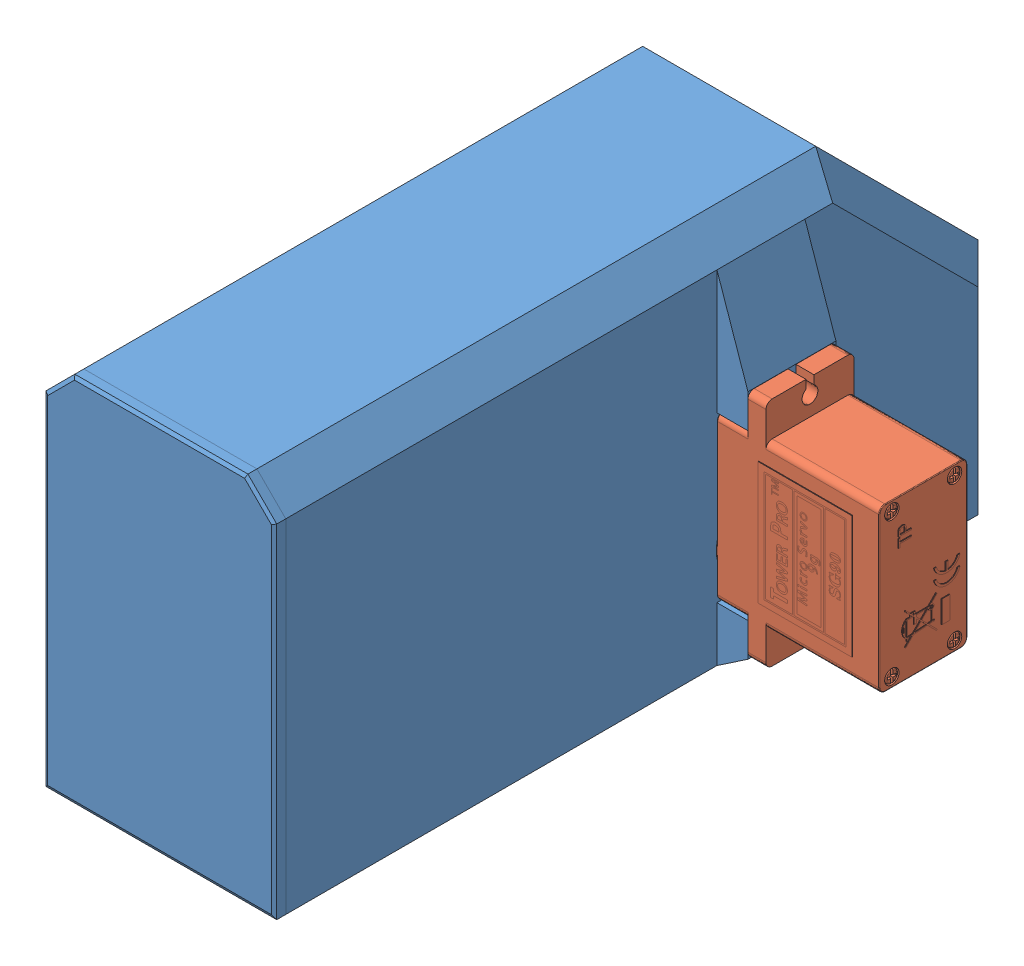
SolidWorks assembly Сборка1, configuration По умолчанию. Lengths in mm.
Overall size (58.9 54.12 101.5).
4 component instances, 4 part files, 9 mates.
Components (placement in the parent):
- кормушка 2-1: кормушка 2 [По умолчанию] at origin size (40.6 51.52 101.5)
- SG90 - Micro Servo 9g - Tower Pro-1: SG90 - Micro Servo 9g - Tower Pro [По умолчанию] at (44.7678 -13.4833 6.3168) x (0 1 0) z (0 0 1) size (32.1 29.95 12.4)
- SG90 - Micro Servo 9g - Tower Pro.3-1: SG90 - Micro Servo 9g - Tower Pro.3 [Peça] at (6.85 -11.96 34.1) x (0 -0.98697 -0.160905) z (0 0.160905 -0.98697) size (32.1 3.8 6.9)
- вал-1: вал [По умолчанию] at (-16 -11.96 34.1) x (0 -1 0) z (1 0 0) size (16.4 16.4 28.15)
Mates (geometry in assembly coordinates):
- Параллельность1: parallel aligned: plane of кормушка 2-1 through (0 0 100) normal (0 0 1); plane of SG90 - Micro Servo 9g - Tower Pro-1 through (22.8 -17.21 40.2) normal (0 0 1)
- Совпадение3: coincident anti-aligned: plane of кормушка 2-1 through (16 25.76 100) normal (1 0 0); plane of SG90 - Micro Servo 9g - Tower Pro-1 through (16 -17.21 39.35) normal (-1 0 0)
- Расстояние1: distance = 2.9 mm aligned: plane of SG90 - Micro Servo 9g - Tower Pro-1 through (20.3 -22.86 39.35) normal (0 -1 0); plane of кормушка 2-1 through (-16 -25.76 100) normal (0 -1 0)
- Совпадение5: coincident aligned: plane of кормушка 2-1 through (20.3 -25.76 28) normal (0 0 -1); plane of SG90 - Micro Servo 9g - Tower Pro-1 through (22.8 -17.21 28) normal (0 0 -1)
- Концентричный1: concentric aligned: circle of SG90 - Micro Servo 9g - Tower Pro-1; circle of SG90 - Micro Servo 9g - Tower Pro.3-1
- Совпадение6: coincident anti-aligned: plane of SG90 - Micro Servo 9g - Tower Pro-1 through (8.65 -11.96 34.1) normal (-1 0 0); plane of SG90 - Micro Servo 9g - Tower Pro.3-1 through (8.65 -11.96 34.1) normal (1 0 0)
- Концентричный2: concentric anti-aligned: circle of SG90 - Micro Servo 9g - Tower Pro.3-1; circle of вал-1
- Совпадение7: coincident anti-aligned: circle of SG90 - Micro Servo 9g - Tower Pro.3-1; plane of вал-1 through (10.65 -11.96 34.1) normal (1 0 0)
- Параллельность2: parallel anti-aligned: plane of SG90 - Micro Servo 9g - Tower Pro-1 through (22.8 -17.21 40.2) normal (0 0 1); plane of вал-1 through (-16 -11.96 34.1) normal (0 0 -1)
